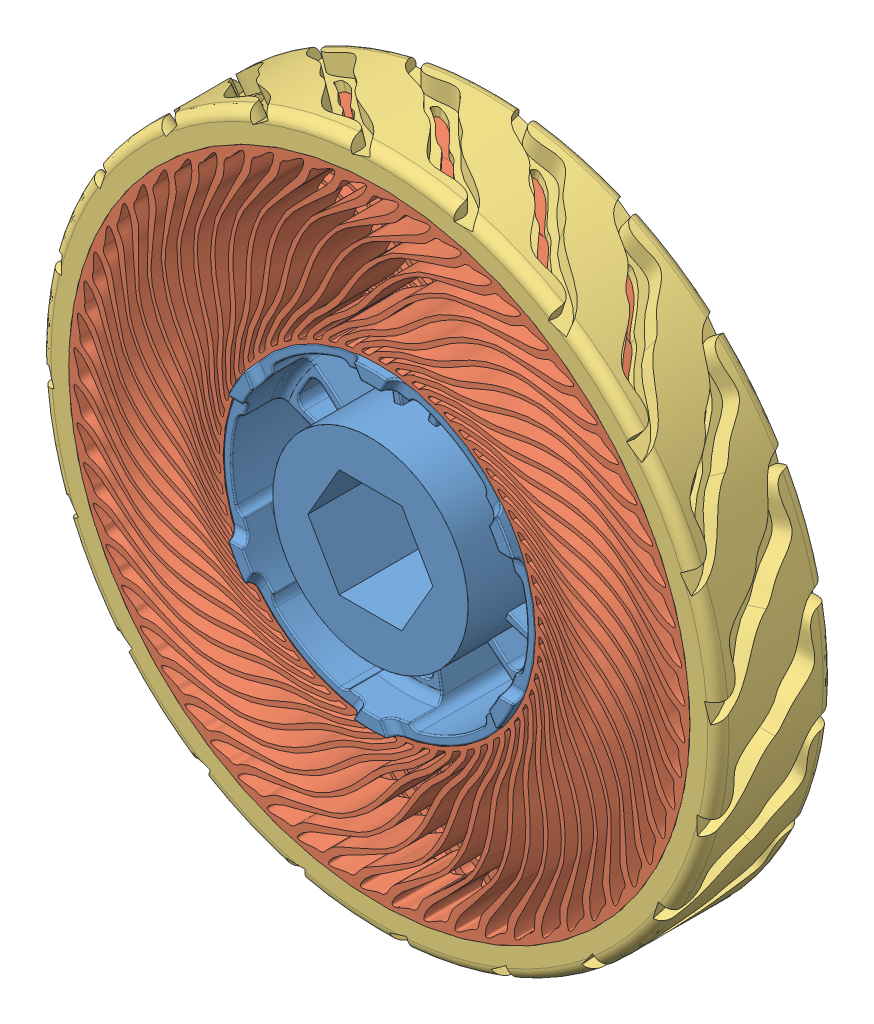
SolidWorks assembly Wheel assembly, configuration Default. Lengths in mm.
Overall size (268.04 347.87 27.14).
4 component instances, 3 part files, 3 mates.
Components (placement in the parent):
- Inner-1: Inner [Default] at (-58.6802 -75.3476 128.587) size (35.2 35.2 14.01)
- Middle-1: Middle [Default] at (-58.8525 -75.1169 133.3281) size (266.7 347.87 13.57)
- Middle-2: Middle [Default] at (209.184 -75.1169 160.4703) x (-1 0 0) z (0 0 -1) size (266.7 347.87 13.57)
- Outer-1: Outer [Default] at (75.1659 100.2568 126.1735) size (76.53 76.53 13.15)
Mates (geometry in assembly coordinates):
- Coincident1: coincident anti-aligned: plane of Inner-1 through (75.1658 100.2565 140.3992) normal (0 0 -1); circle of Middle-1
- Coincident2: coincident anti-aligned: circle of Middle-1; circle of Middle-2
- ProfileCenter2: profile center anti-aligned: circle of Outer-1; circle of Middle-2
